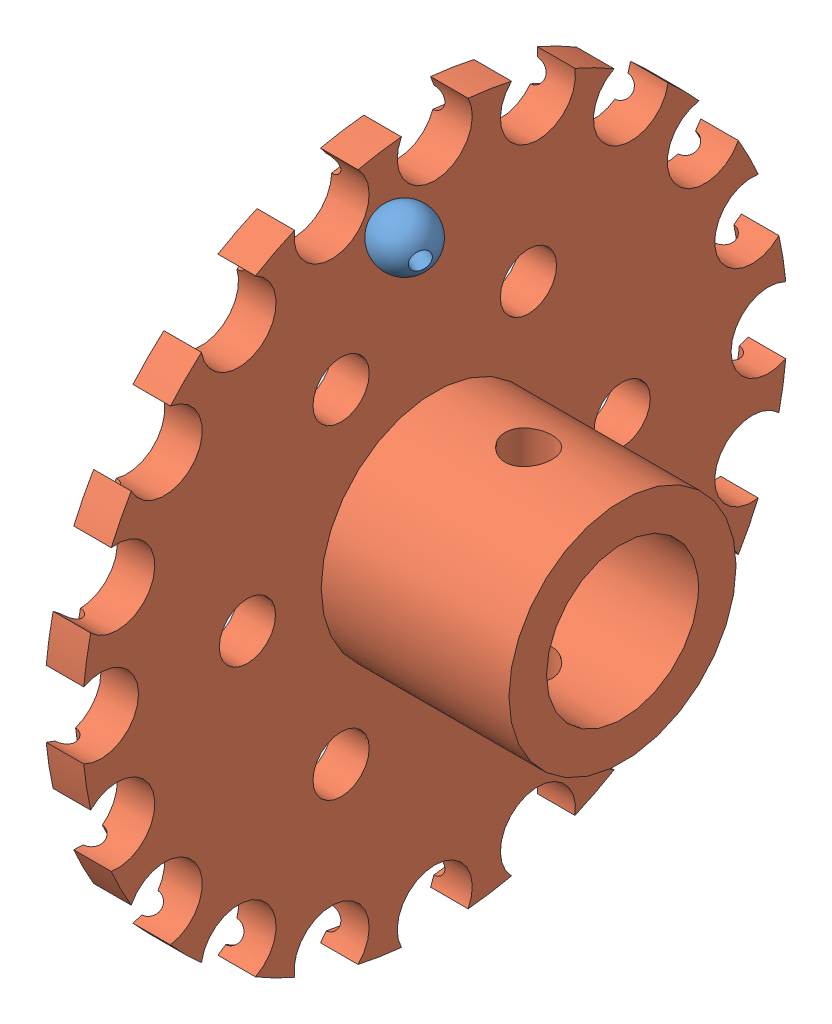
SolidWorks assembly Follower_wheelVER2, configuration Default. Lengths in mm.
Overall size (12.03 38.36 37.39).
2 component instances, 2 part files, 3 mates.
Components (placement in the parent):
- Fishing_bead-1: Fishing_bead [Default] at (5.5341 17.4921 5.1411) x (-0.067512 0.880367 0.469464) z (-0.351242 -0.461387 0.81471) size (3 2.83 3)
- Follower Wheel_VER2-1: Follower Wheel_VER2 [Default] at (1 0 0) size (12.03 37.39 37.39)
Mates (geometry in assembly coordinates):
- Coincident1: coincident anti-aligned: plane of Follower Wheel_VER2-1 through (0 0 0) normal (-1 0 0)
- Coincident2: coincident aligned: plane of Follower Wheel_VER2-1 through (1 0 0) normal (0 1 0)
- Coincident3: coincident aligned: plane of Follower Wheel_VER2-1 through (1 0 0) normal (0 0 1)
